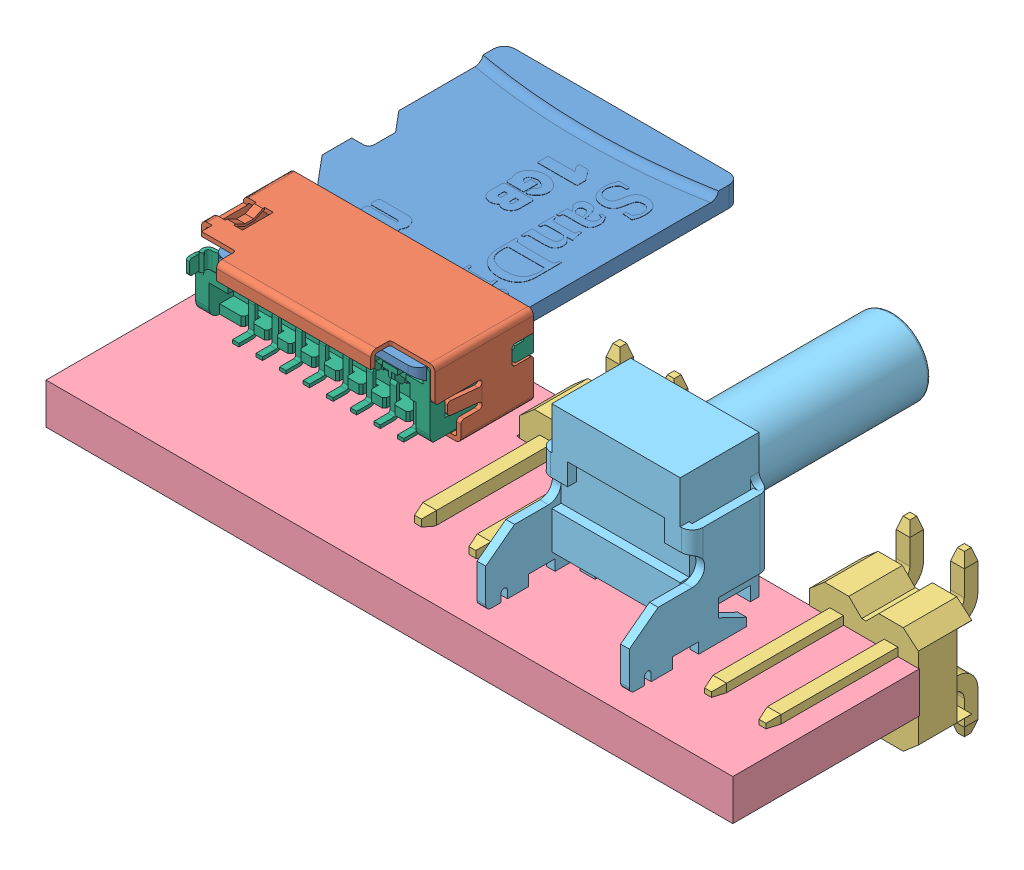
SolidWorks assembly TF slot assm, configuration Default. Lengths in mm.
Overall size (32.07 11.96 20.5).
8 component instances, 6 part files, 5 mates.
Components (placement in the parent):
- User Library-Micro_SD-1: User Library-Micro_SD [Default] at (-14.5274 1.7305 -6.8905) x (0 0 1) z (-1 0 0) size (15 1 11.33)
- 473093751-1: 473093751 [Default] at (-14.0468 0.2405 -2.0758) size (11.4 3.75 5.5)
  - 473093751-1: 473093751 [Default] at origin size (11.4 3.75 5.5)
- pin_header_a-sl254-dg-g04mp1-1: pin_header_a-sl254-dg-g04mp1 [Default] at (8.5658 -2.3633 -5.0916) x (1 0 0) z (0 1 0) size (5.08 9.74 7.5)
- pin_header_a-sl254-dg-g04mp1-2: pin_header_a-sl254-dg-g04mp1 [Default] at (-4.9776 -2.1458 -5.0876) x (1 0 0) z (0 1 0) size (5.08 9.74 7.5)
- TF PCB-1: TF PCB [Default] at (-2.7801 -3.0645 1.9483) x (1 0 0) z (0 1 0) size (32.07 11.3 1.91)
- FSMRA7JH-1: FSMRA7JH [Default] at (1.8518 2.8537 -1.4141) x (-1 0 0) z (0 0 -1) size (8.41 10.52 15.86)
- Untitled-1: Untitled [Default] at (108.7996 1.2114 13.0533) x (-1 0 0) z (0 0 -1) size (11.4 3.52 5.3)
Mates (geometry in assembly coordinates):
- Parallel1: parallel anti-aligned: plane of TF PCB-1 through (11.1514 -3.0645 6.1139) normal (0 0 1); plane of Untitled-1 through (-7.6214 -1.4565 -4.3743) normal (0 0 -1)
- Parallel2: parallel anti-aligned: plane of TF PCB-1 through (-0.2786 -1.1595 1.7528) normal (0 1 0); plane of Untitled-1 through (-19.2614 -1.1095 -0.5793) normal (0 -1 0)
- Coincident4: coincident anti-aligned: plane of TF PCB-1 through (-0.2786 -1.1595 1.7528) normal (0 1 0); plane of Untitled-1 through (-10.9814 -1.1595 0.9407) normal (0 -1 0)
- Coincident6: coincident anti-aligned: plane of 473093751-1/473093751-1 through (-20.0468 1.642 -3.3743) normal (0 0 -1); plane of Untitled-1 through (-20.7014 -1.1485 -3.3743) normal (0 0 1)
- Distance1: distance = 0.0254 mm anti-aligned: plane of 473093751-1/473093751-1 through (-19.8468 2.3905 -4.3758) normal (1 0 0); plane of Untitled-1 through (-19.8214 -0.8415 -5.0743) normal (-1 0 0)
